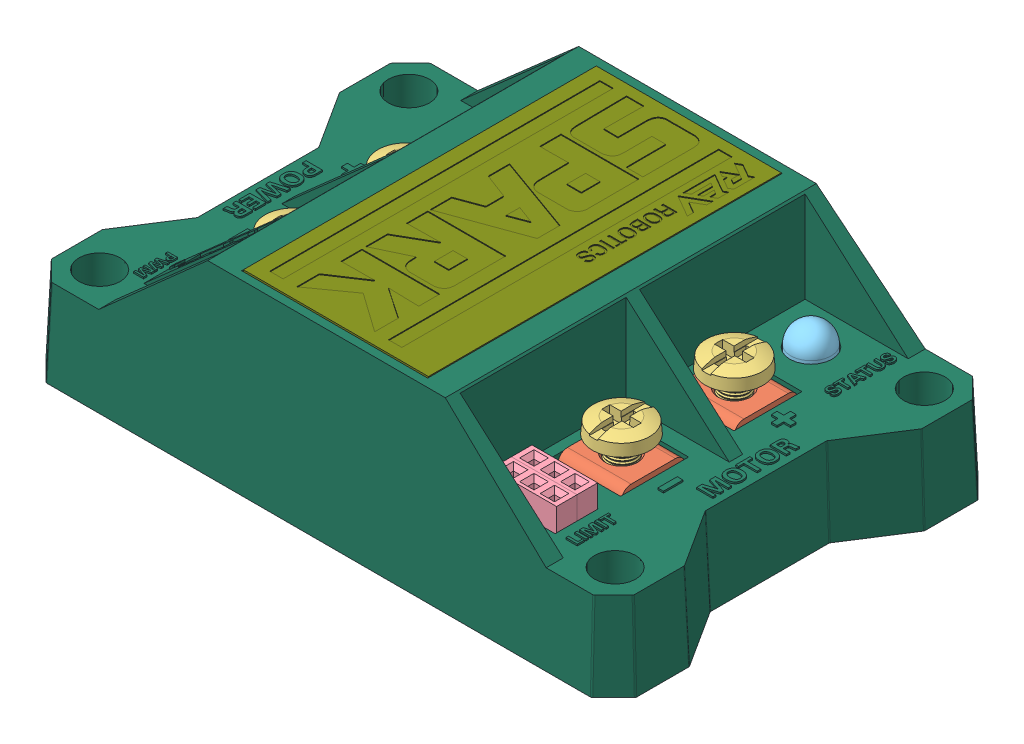
SolidWorks assembly REV_SPARK, configuration Default. Lengths in mm.
Overall size (73.01 27.38 47.86).
36 component instances, 17 part files, 0 mates.
Components (placement in the parent):
- RR-SPARK-BD-B-Assembly-1: RR-SPARK-BD-B-Assembly [Default] at (2.3249 6.4587 12.2534) size (55.12 26.11 42.42)
  - RR-SPARK-BD-B-1: RR-SPARK-BD-B [Default] at (27.8945 25.8332 38.0904) size (53.34 3.8 40.64)
  - ScrewTerminalAssembly-1: ScrewTerminalAssembly [Default] at (15.7541 22.7195 39.4261) x (0 0 1) z (-1 0 0) size (7.87 11.69 7.87)
    - ScrewTerminalBase-1: ScrewTerminalBase [Default] at (3.4868 6.6312 8.3972) size (7.87 7.68 7.87)
    - ScrewTerminalScrew-1: ScrewTerminalScrew [Default] at (3.5041 -1.1314 8.5263) x (0.998152 0 -0.060771) z (0.060771 0 0.998152) size (7.16 8.3 7.16)
  - ScrewTerminalAssembly-2: ScrewTerminalAssembly [Default] at (56.3941 22.7195 39.4261) x (0 0 1) z (-1 0 0) size (7.87 11.69 7.87)
    - ScrewTerminalBase-1: ScrewTerminalBase [Default] at (3.4868 6.6312 8.3972) size (7.87 7.68 7.87)
    - ScrewTerminalScrew-1: ScrewTerminalScrew [Default] at (3.5041 -1.1314 8.5263) x (0.998152 0 -0.060771) z (0.060771 0 0.998152) size (7.16 8.3 7.16)
  - ScrewTerminalAssembly-3: ScrewTerminalAssembly [Default] at (15.7541 22.7195 25.4561) x (0 0 1) z (-1 0 0) size (7.87 11.69 7.87)
    - ScrewTerminalBase-1: ScrewTerminalBase [Default] at (3.4868 6.6312 8.3972) size (7.87 7.68 7.87)
    - ScrewTerminalScrew-1: ScrewTerminalScrew [Default] at (3.5041 -1.1314 8.5263) x (0.998152 0 -0.060771) z (0.060771 0 0.998152) size (7.16 8.3 7.16)
  - ScrewTerminalAssembly-4: ScrewTerminalAssembly [Default] at (56.3941 22.7195 25.4561) x (0 0 1) z (-1 0 0) size (7.87 11.69 7.87)
    - ScrewTerminalBase-1: ScrewTerminalBase [Default] at (3.4868 6.6312 8.3972) size (7.87 7.68 7.87)
    - ScrewTerminalScrew-1: ScrewTerminalScrew [Default] at (3.5041 -1.1314 8.5263) x (0.998152 0 -0.060771) z (0.060771 0 0.998152) size (7.16 8.3 7.16)
  - Header-Female-1x3-PPTC031LFBN-RC-1: Header-Female-1x3-PPTC031LFBN-RC [Default] at (7.5745 27.4332 53.3304) size (8.13 15.71 2.54)
  - Header-Female-1x3-PPTC031LFBN-RC-2: Header-Female-1x3-PPTC031LFBN-RC [Default] at (48.2145 27.4332 53.3304) size (8.13 15.71 2.54)
  - Header-Female-1x3-PPTC031LFBN-RC-3: Header-Female-1x3-PPTC031LFBN-RC [Default] at (48.2145 27.4332 55.8704) size (8.13 15.71 2.54)
  - LED-RGB-ThroughHole-1: LED-RGB-ThroughHole [Default] at (48.2145 27.4332 21.5804) x (-1 0 0) z (0 0 -1) size (5.45 12.2 5.9)
  - MOSFET-PSMN1R0-30YLC115-1: MOSFET-PSMN1R0-30YLC115 [Default] at (35.6415 27.4332 27.2954) x (0 0 -1) z (1 0 0) size (5 1.2 6.72)
  - MOSFET-PSMN1R0-30YLC115-2: MOSFET-PSMN1R0-30YLC115 [Default] at (36.5305 27.4332 33.6454) size (5 1.2 6.72)
  - MOSFET-PSMN1R0-30YLC115-3: MOSFET-PSMN1R0-30YLC115 [Default] at (36.5305 27.4332 42.5354) x (-1 0 0) z (0 0 -1) size (5 1.2 6.72)
  - MOSFET-PSMN1R0-30YLC115-4: MOSFET-PSMN1R0-30YLC115 [Default] at (35.6415 27.4332 48.8854) x (0 0 -1) z (1 0 0) size (5 1.2 6.72)
  - Varistor-1: Varistor [Default] at (52.6595 27.4332 22.5964) x (0 0 1) z (-1 0 0) size (3.4 1.02 1.45)
  - Varistor-2: Varistor [Default] at (41.2295 27.4332 53.7114) x (0 0 1) z (-1 0 0) size (3.4 1.02 1.45)
  - Crystal-1: Crystal [Default] at (17.9885 27.4332 48.3774) x (0 0 1) z (-1 0 0) size (5.2 1.5 3.4)
  - Button-PTS645SM43SMTR92LFS-1: Button-PTS645SM43SMTR92LFS [Default] at (8.0825 27.4332 21.5804) size (9 4.3 6)
  - OptoIsolator-TLP118-1: OptoIsolator-TLP118 [Default] at (14.1785 27.4332 50.4094) x (0 0 -1) z (1 0 0) size (7.02 2.2 3.7)
  - GateDriver-A4940KLPTR-T-1: GateDriver-A4940KLPTR-T [Default] at (30.1805 25.8332 53.9654) x (0 0 -1) z (-1 0 0) size (7.8 1.2 6.43)
  - MCU-PIC16F1828-I-GZ-1: MCU-PIC16F1828-I-GZ [Default] at (19.0045 25.8332 52.8224) x (-1 0 0) z (0 0 1) size (4 0.55 4)
  - Capacitor-UCL1V471MNL1GS-1: Capacitor-UCL1V471MNL1GS [Default] at (25.8625 27.4332 46.5994) x (0 0 1) z (-1 0 0) size (10.5 14.3 11.5)
  - Capacitor-UCL1V471MNL1GS-2: Capacitor-UCL1V471MNL1GS [Default] at (25.8625 27.4332 25.2634) x (0 0 1) z (-1 0 0) size (10.5 14.3 11.5)
  - Capacitor-UCL1V471MNL1GS-3: Capacitor-UCL1V471MNL1GS [Default] at (25.8625 27.4332 35.9314) x (0 0 -1) z (1 0 0) size (10.5 14.3 11.5)
  - 1mmborder-1: 1mmborder [Default] at (27.8945 25.8332 38.0904) size (55.12 1.6 42.42)
- Spark_P01-REV-41_TOPSHELL-1: Spark_P01-REV-41_TOPSHELL [Default] at (30.1178 29.0303 87.4264) x (1 0 0) z (0 1 0) size (73.01 47.86 22.14)
- heatsink-1: heatsink [Default] at (29.9048 43.475 28.4732) size (25.78 15.52 43.69)
- Spark_P01-REV-41_bottom_cover-1: Spark_P01-REV-41_bottom_cover [Default] at (30.1178 29.0303 87.4264) x (1 0 0) z (0 -1 0) size (65.7 43.71 2.65)
